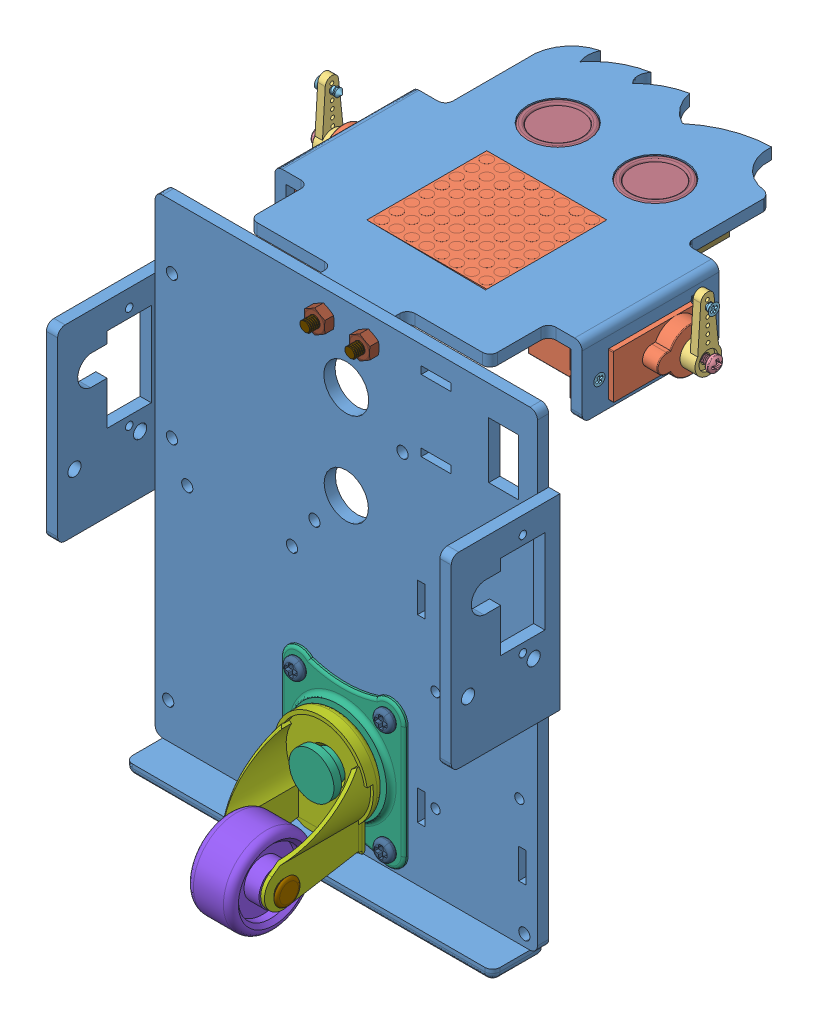
SolidWorks assembly DYOR_3D_LM_AR, configuration Predeterminado. Lengths in mm.
Overall size (108 136.43 131.4).
50 component instances, 20 part files, 22 mates.
Components (placement in the parent):
- Base-1: Base [Predeterminado] at (60.418 -80.9125 12.5389) size (108 128.45 29)
- AR1-1: AR1 [Predeterminado] at (-137 230.6023 -137.861) size (34.06 21.84 31.9)
  - sg90-2: sg90 [Default] at (126.818 -193.0635 98.9775) x (0 0 1) z (0 -1 0) size (31.9 29.9 11.8)
  - SG90 plastic Horn-2: SG90 plastic Horn [Default] at (97.368 -198.9635 104.8775) x (0 0.999767 0.021606) z (0 -0.021606 0.999767) size (19.4 4 7.07)
  - (M2_3_mm)_90116A007_METRIC 316 SS PAN HEAD PHILLIPS MACHINE SCREW-2: (M2_3_mm)_90116A007_METRIC 316 SS PAN HEAD PHILLIPS MACHINE SCREW [90116A007] at (97.368 -198.9635 104.8775) x (0 0 1) z (-1 0 0) size (4 4 4.68)
  - M2x6 SelfTap Screw-1: M2x6 SelfTap Screw [Predeterminado] at (93.868 -186.4635 104.8775) x (0 0.924225 0.381849) z (-1 0 0) size (3.4 3.28 6)
  - M2x6 SelfTap Screw-3: M2x6 SelfTap Screw [Predeterminado] at (105.418 -198.9635 123.8775) x (0 0.924225 0.381849) z (-1 0 0) size (3.4 3.28 6)
  - M2x6 SelfTap Screw-5: M2x6 SelfTap Screw [Predeterminado] at (105.418 -198.9635 96.5775) x (0 0.924225 0.381849) z (-1 0 0) size (3.4 3.28 6)
- AR2-1: AR2 [Predeterminado] at (-146.3584 230.6023 -137.861) size (34.06 21.82 31.9)
  - sg90-1: sg90 [Default] at (175.3764 -204.8635 98.9775) x (0 0 1) z (0 1 0) size (31.9 29.9 11.8)
  - SG90 plastic Horn-1: SG90 plastic Horn [Default] at (204.8264 -198.9635 104.8775) x (0 0.999858 0.016879) z (0 0.016879 -0.999858) size (19.4 4 7.07)
  - (M2_3_mm)_90116A007_METRIC 316 SS PAN HEAD PHILLIPS MACHINE SCREW-1: (M2_3_mm)_90116A007_METRIC 316 SS PAN HEAD PHILLIPS MACHINE SCREW [90116A007] at (204.8264 -198.9635 104.8775) x (0 0 -1) z (1 0 0) size (4 4 4.68)
  - M2x6 SelfTap Screw-2: M2x6 SelfTap Screw [Predeterminado] at (208.3264 -186.4635 104.8775) x (0 -0.924225 -0.381849) z (1 0 0) size (3.4 3.28 6)
  - M2x6 SelfTap Screw-4: M2x6 SelfTap Screw [Predeterminado] at (196.7764 -198.9635 123.8775) x (0 -0.924225 -0.381849) z (1 0 0) size (3.4 3.28 6)
  - M2x6 SelfTap Screw-6: M2x6 SelfTap Screw [Predeterminado] at (196.7764 -198.9635 96.5775) x (0 -0.924225 -0.381849) z (1 0 0) size (3.4 3.28 6)
- CA-1: CA [Predeterminado] at (-2.207 18.0036 0) size (33 45.94 43.2)
  - Caster Wheel-1: Caster Wheel [Default] at (57.6387 -78.841 57.7572) x (0 1 0) z (-1 0 0) size (45.94 37.59 33)
    - caster holder-1: caster holder [Default] at (-24.0751 44.7184 29.5137) x (1 0 0) z (0 0 -1) size (39 9.27 33)
    - holder-1: holder [Default] at (-1.5751 42.9484 46.0137) x (0 0 1) z (1 0 0) size (25 28.07 31.31)
    - caster wheel-1: caster wheel [Default] at (-15.6961 19.9484 46.0137) x (0.997275 0.073773 0) z (0 0 1) size (23 23 14)
    - Part4-1: Part4 [Default] at (-15.6961 19.9484 55.0137) x (-0.978448 0.206495 0) z (0 0 -1) size (7 7 20)
  - M3x6 Philips Screw-1: M3x6 Philips Screw [Predeterminado] at (23.625 -65.4161 13.5389) size (5.3 5.3 7.81)
  - M3x6 Philips Screw-2: M3x6 Philips Screw [Predeterminado] at (-0.375 -65.4161 13.5389) size (5.3 5.3 7.81)
  - M3x6 Philips Screw-3: M3x6 Philips Screw [Predeterminado] at (-0.375 -95.4161 13.5389) size (5.3 5.3 7.81)
  - M3x6 Philips Screw-4: M3x6 Philips Screw [Predeterminado] at (23.625 -95.4161 13.5389) size (5.3 5.3 7.81)
  - M3 Nut-1: M3 Nut [Predeterminado] at (23.625 -65.4161 11.0389) size (6.27 6.27 2.71)
  - M3 Nut-2: M3 Nut [Predeterminado] at (-0.375 -65.4161 11.0389) size (6.27 6.27 2.71)
  - M3 Nut-3: M3 Nut [Predeterminado] at (-0.375 -95.4161 11.0389) size (6.27 6.27 2.71)
  - M3 Nut-4: M3 Nut [Predeterminado] at (23.625 -95.4161 11.0389) size (6.27 6.27 2.71)
- HC-SR04 Ping Sensor-1: HC-SR04 Ping Sensor [Default] at (9.418 28.7888 -56.8835) x (0 0 -1) z (0 1 0) size (25.18 45 18.07)
  - PCB-1: PCB [Default] at origin size (20.5 45 1.75)
  - Transducer-1: Transducer [Default] at (0 -13 13.25) x (1 0 0) z (0 -1 0) size (15.88 12 15.88)
  - Transducer-2: Transducer [Default] at (0 13 13.25) x (1 0 0) z (0 -1 0) size (15.88 12 15.88)
  - 3 Pin Header 90 Degree-1: 3 Pin Header 90 Degree [Default] at (8.4275 0 -1.25) x (-1 0 0) z (0 -1 0) size (8 7.82 10)
  - 14 Pin SMT-1: 14 Pin SMT [Default] at (-0.35 -18.5 -0.85) x (0 -1 0) z (1 0 0) size (6 1.6 8.8)
  - 14 Pin SMT-2: 14 Pin SMT [Default] at (0 -0.3826 -0.85) x (1 0 0) z (0 1 0) size (6 1.6 8.8)
  - 14 Pin SMT-3: 14 Pin SMT [Default] at (0 17.5274 -0.85) x (1 0 0) z (0 1 0) size (6 1.6 8.8)
  - Cap1 SMT-1: Cap1 SMT [Default] at (-1.755 7.4774 -0.9689) x (0 1 0) z (-1 0 0) size (4.5 1.84 1.75)
  - Cap1 SMT-2: Cap1 SMT [Default] at (6.835 7.4774 -0.9689) x (0 1 0) z (-1 0 0) size (4.5 1.84 1.75)
  - Cap1 SMT-3: Cap1 SMT [Default] at (-6.835 7.4774 -0.9689) x (0 1 0) z (-1 0 0) size (4.5 1.84 1.75)
  - Cap1 SMT-4: Cap1 SMT [Default] at (4.295 7.4774 -0.9689) x (0 1 0) z (-1 0 0) size (4.5 1.84 1.75)
  - Cap1 SMT-5: Cap1 SMT [Default] at (1.755 7.4774 -0.9689) x (0 1 0) z (-1 0 0) size (4.5 1.84 1.75)
  - Cap1 SMT-6: Cap1 SMT [Default] at (-4.295 7.4774 -0.9689) x (0 1 0) z (-1 0 0) size (4.5 1.84 1.75)
  - HC-SR04 Crystal-1: HC-SR04 Crystal [Default] at (-8.3 0 1.75) x (0 -1 0) z (0 0 1) size (10 3.5 2.7)
- M3x10 Philips Screw-1: M3x10 Philips Screw [Predeterminado] at (3.418 36.0388 7.5389) x (-0.459458 -0.8882 0) z (0 0 -1) size (5.3 5.3 11.8)
- M3x10 Philips Screw-2: M3x10 Philips Screw [Predeterminado] at (15.418 36.0388 7.5389) x (-0.386504 -0.922288 0) z (0 0 -1) size (5.3 5.3 11.8)
- M3 Nut-1: M3 Nut [Predeterminado] at (15.418 36.0388 16.5389) size (6.27 6.27 2.71)
- M3 Nut-2: M3 Nut [Predeterminado] at (3.418 36.0388 16.5389) size (6.27 6.27 2.71)
- Front_LM_AR-1: Front_LM_AR [Predeterminado] at (-117.7101 39.5388 -112.8127) x (1 0 0) z (0 1 0) size (82 90.81 18.8)
- max7219_compact_board-1: max7219_compact_board [Predeterminado] at (15.9172 28.3388 -24.9391) x (1 0 0) z (0 1 0) size (34 32 21.83)
Mates (geometry in assembly coordinates):
- Coincidente23: coincident: plane of Base-1 through (-39.582 40.5388 12.5389) normal (0 0 1); plane of CA-1/Caster Wheel-1/caster holder-1 through (9.418 -17.6143 12.5389) normal (0 0 -1)
- Concéntrica1: concentric: circle of Base-1; circle of CA-1/Caster Wheel-1/caster holder-1
- Concéntrica2: concentric: circle of Base-1; circle of CA-1/Caster Wheel-1/caster holder-1
- Coincidente30: coincident: plane of Base-1 through (-39.582 40.5388 12.5389) normal (0 0 1); plane of M3 Nut-1 through (15.418 36.0388 12.5389) normal (0 0 -1)
- Coincidente31: coincident: plane of Base-1 through (-39.582 40.5388 12.5389) normal (0 0 1); plane of M3 Nut-2 through (3.418 36.0388 12.5389) normal (0 0 -1)
- Concéntrica7: concentric: circle of Base-1; circle of M3 Nut-1
- Concéntrica8: concentric: circle of Base-1; circle of M3 Nut-2
- Coincidente32: coincident: plane of Base-1 through (-39.582 40.5388 9.5389) normal (0 0 -1); plane of Front_LM_AR-1 through (-0.582 42.5388 9.5389) normal (0 0 1)
- Concéntrica9: concentric: circle of Base-1; circle of Front_LM_AR-1
- Paralelo1: parallel: plane of Base-1 through (-39.582 42.5388 9.5389) normal (0 1 0); plane of Front_LM_AR-1 through (-2.582 42.5388 8.3059) normal (0 1 0)
- Concéntrica10: concentric: circle of HC-SR04 Ping Sensor-1/Transducer-1; circle of Front_LM_AR-1
- Concéntrica11: concentric: circle of HC-SR04 Ping Sensor-1/Transducer-2; circle of Front_LM_AR-1
- Coincidente34: coincident: plane of HC-SR04 Ping Sensor-1/Transducer-2 through (-3.582 42.5388 -64.8235) normal (0 1 0); plane of Front_LM_AR-1 through (-2.582 42.5388 8.3059) normal (0 1 0)
- Coincidente37: coincident: plane of AR2-1/sg90-1 through (29.018 37.5388 -38.8835) normal (0 0 -1); plane of Front_LM_AR-1 through (47.418 25.7388 -38.8835) normal (0 0 1)
- Coincidente39: coincident: plane of AR1-1/sg90-2 through (-10.182 25.7388 -38.8835) normal (0 0 -1); plane of Front_LM_AR-1 through (-28.582 25.7388 -38.8835) normal (0 0 1)
- Coincidente41: coincident: plane of AR1-1/sg90-2 through (-10.182 37.5388 -38.8835) normal (0 1 0); plane of Front_LM_AR-1 through (-28.582 37.5388 -38.8835) normal (0 -1 0)
- Coincidente42: coincident: plane of AR2-1/sg90-1 through (29.018 37.5388 -38.8835) normal (0 1 0); plane of Front_LM_AR-1 through (47.418 37.5388 -38.8835) normal (0 -1 0)
- Coincidente43: coincident: plane of AR2-1/sg90-1 through (47.418 25.7388 -43.5835) normal (1 0 0); plane of Front_LM_AR-1 through (47.418 23.7388 -45.8835) normal (-1 0 0)
- Coincidente44: coincident: plane of AR1-1/sg90-2 through (-28.582 37.5388 -43.5835) normal (-1 0 0); plane of Front_LM_AR-1 through (-28.582 23.7388 -45.8835) normal (1 0 0)
- Coincidente45: coincident: plane of Front_LM_AR-1 through (25.4172 42.5388 -40.9391) normal (0 0 1); plane of max7219_compact_board-1 through (-6.5828 42.5388 -40.9391) normal (0 0 -1)
- Coincidente46: coincident: plane of Front_LM_AR-1 through (25.4172 42.5388 -8.6065) normal (-1 0 0); plane of max7219_compact_board-1 through (25.4172 42.5388 -40.9391) normal (1 0 0)
- Coincidente47: coincident: plane of Front_LM_AR-1 through (-2.582 42.5388 8.3059) normal (0 1 0); plane of max7219_compact_board-1 through (15.9172 42.5388 -24.9391) normal (0 1 0)
